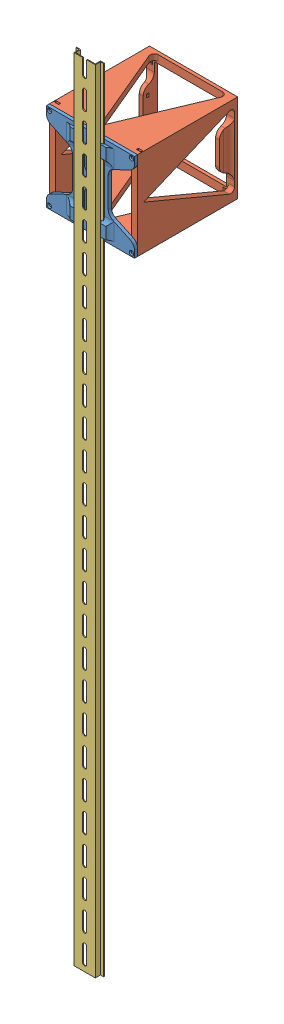
SolidWorks assembly Parts, configuration Standard. Lengths in mm.
Overall size (113 1000 138).
3 component instances, 3 part files, 5 mates.
Components (placement in the parent):
- Din-Rail-1: Din-Rail [Standard] at (-24.1452 11.3139 107.5) size (111.5 111.5 7.2)
- Holder-1: Holder [Standard] at (-24.1452 11.3139 -19) size (113 111.5 126.5)
- Hutschiene-1: Hutschiene [Standard] at (-23.8952 -849.7872 119) x (1 0 0) z (0 1 0) size (35 7.5 1000)
Mates (geometry in assembly coordinates):
- Deckungsgleich1: coincident anti-aligned: plane of Din-Rail-1 through (21.6048 58.3923 107.5) normal (0 0 -1); plane of Holder-1 through (-24.1452 11.3139 107.5) normal (0 0 1)
- Konzentrisch1: concentric aligned: cylinder of Din-Rail-1 through (27.8548 63.3139 107.5) axis (0 0 1) radius 1.6; cylinder of Holder-1 through (27.8548 63.3139 87.5) axis (0 0 1) radius 1.6
- Konzentrisch2: concentric aligned: cylinder of Din-Rail-1 through (-76.1452 -40.6861 107.5) axis (0 0 1) radius 1.6; cylinder of Holder-1 through (-76.1452 -40.6861 87.5) axis (0 0 1) radius 1.6
- Deckungsgleich2: coincident anti-aligned: plane of Din-Rail-1 through (21.6048 58.3923 111.5) normal (0 0 1); plane of Hutschiene-1 through (-36.3952 150.2128 111.5) normal (0 0 -1)
- Deckungsgleich3: coincident anti-aligned: plane of Din-Rail-1 through (-6.3952 -24.4361 112.7) normal (-1 0 0); plane of Hutschiene-1 through (-6.3952 150.2128 112.5) normal (1 0 0)
